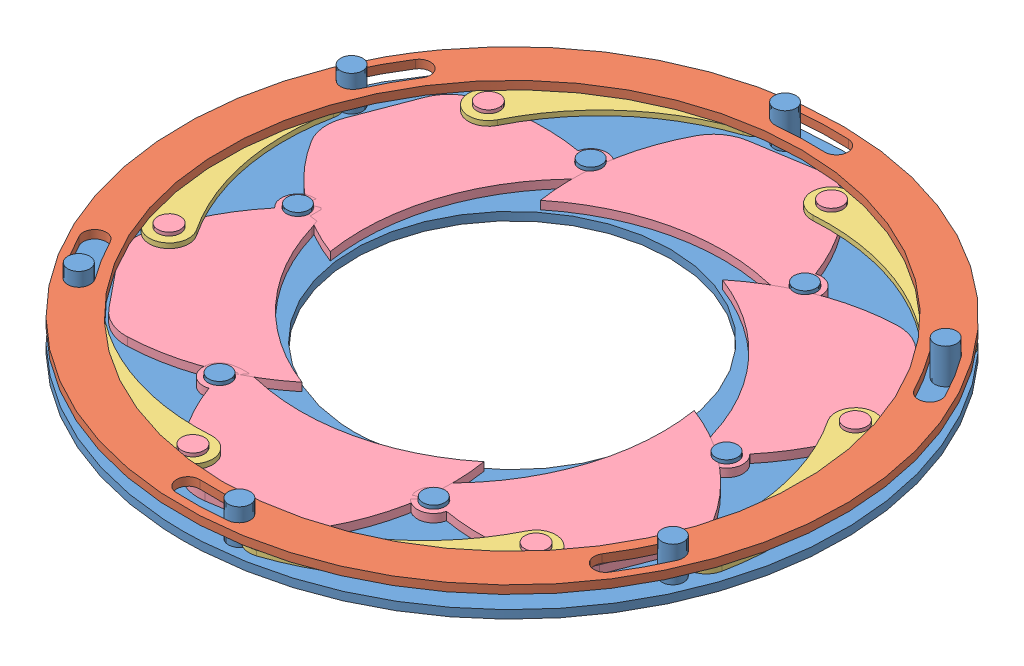
SolidWorks assembly Iris Mechanism assembly, configuration Default. Lengths in mm.
Overall size (124.36 5.93 124.36).
14 component instances, 4 part files, 7 mates.
Components (placement in the parent):
- 1.Base-2: 1.Base [Default] at origin size (90 5.93 90)
- 2. ring-1: 2. ring [Default] at (0 2.925 0) x (-0.540229 0 0.841518) z (-0.841518 0 -0.540229) size (90 2.26 90)
- 3.balt-1: 3.balt [Default] at (-26.9182 3.025 104.2414) x (-0.395977 0 0.91826) z (-0.91826 0 -0.395977) size (9.08 0.68 31.15)
- 4.Silder balt-1: 4.Silder balt [Default] at (-57.9594 1.125 25.1929) x (-0.987277 0 0.159011) z (-0.159011 0 -0.987277) size (31.3 2.26 19.8)
- 4.Silder balt-7: 4.Silder balt [Default] at (-7.162 1.125 62.7908) x (-0.355931 0 0.934512) z (-0.934512 0 -0.355931) size (31.3 2.26 19.8)
- 4.Silder balt-8: 4.Silder balt [Default] at (50.7974 1.125 37.5979) x (0.631346 0 0.775501) z (-0.775501 0 0.631346) size (31.3 2.26 19.8)
- 4.Silder balt-9: 4.Silder balt [Default] at (57.9594 1.125 -25.1929) x (0.987277 0 -0.159011) z (0.159011 0 0.987277) size (31.3 2.26 19.8)
- 4.Silder balt-10: 4.Silder balt [Default] at (7.162 1.125 -62.7908) x (0.355931 0 -0.934512) z (0.934512 0 0.355931) size (31.3 2.26 19.8)
- 4.Silder balt-11: 4.Silder balt [Default] at (-50.7974 1.125 -37.5979) x (-0.631346 0 -0.775501) z (0.775501 0 -0.631346) size (31.3 2.26 19.8)
- 3.balt-7: 3.balt [Default] at (76.8166 3.025 75.4326) x (0.597248 0 0.802056) z (-0.802056 0 0.597248) size (9.08 0.68 31.15)
- 3.balt-8: 3.balt [Default] at (103.7348 3.025 -28.8089) x (0.993225 0 -0.116204) z (0.116204 0 0.993225) size (9.08 0.68 31.15)
- 3.balt-9: 3.balt [Default] at (26.9182 3.025 -104.2414) x (0.395977 0 -0.91826) z (0.91826 0 0.395977) size (9.08 0.68 31.15)
- 3.balt-10: 3.balt [Default] at (-76.8166 3.025 -75.4326) x (-0.597248 0 -0.802056) z (0.802056 0 -0.597248) size (9.08 0.68 31.15)
- 3.balt-11: 3.balt [Default] at (-103.7348 3.025 28.8089) x (-0.993225 0 0.116204) z (-0.116204 0 -0.993225) size (9.08 0.68 31.15)
Mates (geometry in assembly coordinates):
- Distance1: distance = 1.8 mm anti-aligned: plane of 1.Base-2 through (0 3.0625 0) normal (0 1 0); plane of 2. ring-1 through (0 4.8625 0) normal (0 -1 0)
- Concentric1: concentric aligned: cylinder of 1.Base-2 through (0 3.0625 0) axis (0 -1 0) radius 45; cylinder of 2. ring-1 through (0 5.9875 0) axis (0 -1 0) radius 45
- Coincident2: coincident anti-aligned: plane of 1.Base-2 through (0 3.0625 0) normal (0 1 0); plane of 4.Silder balt-1 through (10.1491 3.0625 -8.363) normal (0 -1 0)
- Coincident3: coincident anti-aligned: plane of 3.balt-1 through (20.6354 4.1875 -15.2455) normal (0 -1 0); plane of 4.Silder balt-1 through (10.1491 4.1875 -8.363) normal (0 1 0)
- Concentric14: concentric anti-aligned: circle of 1.Base-2; circle of 4.Silder balt-1
- Concentric16: concentric anti-aligned: circle of 3.balt-1; circle of 4.Silder balt-1
- Concentric17: concentric anti-aligned: circle of 2. ring-1; circle of 3.balt-1
